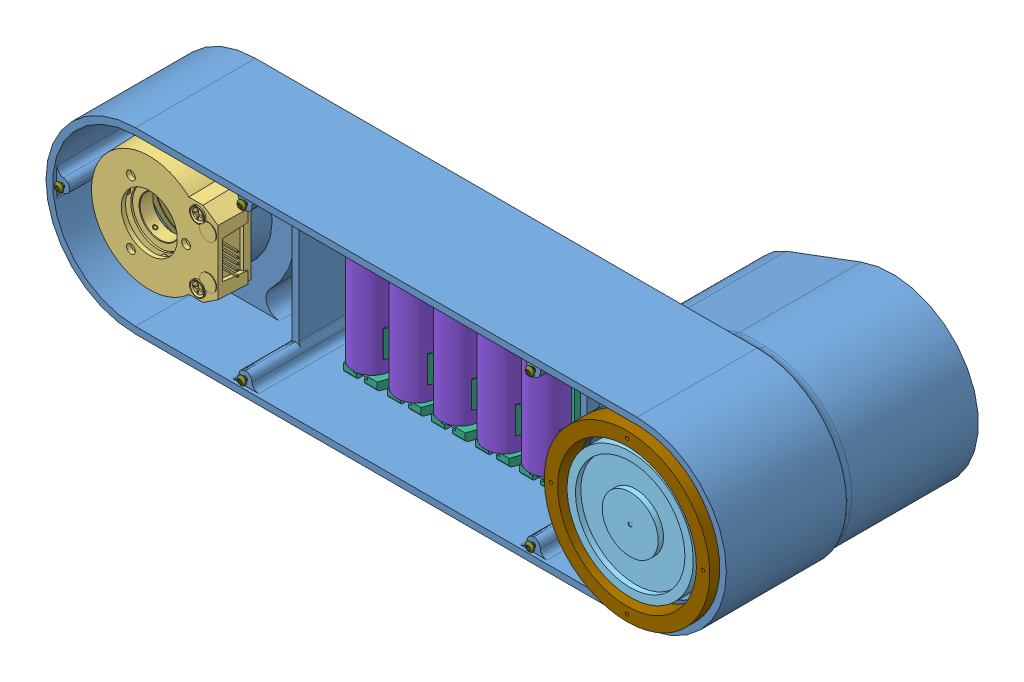
SolidWorks assembly Wall Link, configuration Default. Lengths in mm.
Overall size (323.85 85.09 127.22).
64 component instances, 23 part files, 117 mates.
Components (placement in the parent):
- Wall Link Frame-1: Wall Link Frame [Default] at (-125.008 20.7132 -31.1742) size (323.85 85.09 121.22)
- ring_gear-1: ring_gear [Default] at (-125.008 20.7132 -35.0242) x (0 0 -1) z (1 0 0) size (5 75 75)
- Magnet Encoders E3-X-750-X-H-D-X-1: Magnet Encoders E3-X-750-X-H-D-X [Default] at (113.752 20.7132 -54.2232) x (0 1 0) z (-1 0 0) size (55.98 16.26 66.52)
- magnet holder-1: magnet holder [Default] at (117.5304 22.0262 -2.1382) x (0.944598 0.32823 0) z (-0.32823 0.944598 0) size (50.8 63.9 50.6)
- EM237 Magnet-1: EM237 Magnet [Default] at (113.752 20.7132 10.3713) x (-0.997847 -0.065578 0) z (-0.065578 0.997847 0) size (60.08 25.02 60.08)
- PCB_Battery Assembly-3: PCB_Battery Assembly [Default] at (90.4555 -0.9181 88.7233) x (1 0 0) z (0 1 0) size (117.17 24.87 77.22)
  - Battery Holder - keystone-PN1043-1: Battery Holder - keystone-PN1043 [Default] at (-125.3925 103.3982 18.9155) x (1 0 0) z (0 0 -1) size (20.65 18.93 77.14)
  - Battery PCB-1: Battery PCB [Default] at (-148.3186 115.135 -16.9005) x (1 0 0) z (0 -1 0) size (117.17 77.06 1.59)
  - battery_6612-1: battery_6612 [Default] at (-117.0385 104.4035 -11.3639) x (-0.413992 0.91028 0) z (0.91028 0.413992 0) size (18.3 65.05 18.3)
  - battery_6612-2: battery_6612 [Default] at (-137.9935 104.4035 54.6265) x (-0.916106 0.400937 0) z (-0.400937 -0.916106 0) size (18.3 65.05 18.3)
  - Battery Holder - keystone-PN1043-2: Battery Holder - keystone-PN1043 [Default] at (-129.6396 103.3982 24.3471) x (-1 0 0) z (0 0 1) size (20.65 18.93 77.14)
  - Battery Holder - keystone-PN1043-3: Battery Holder - keystone-PN1043 [Default] at (-104.4375 103.3982 18.9155) x (1 0 0) z (0 0 -1) size (20.65 18.93 77.14)
  - battery_6612-3: battery_6612 [Default] at (-96.0835 104.4035 -10.3735) x (1 0 0) z (0 -1 0) size (18.3 65.05 18.3)
  - Battery Holder - keystone-PN1043-4: Battery Holder - keystone-PN1043 [Default] at (-83.4825 103.3982 18.9155) x (1 0 0) z (0 0 -1) size (20.65 18.93 77.14)
  - Battery Holder - keystone-PN1043-5: Battery Holder - keystone-PN1043 [Default] at (-45.8196 103.3982 24.3471) x (-1 0 0) z (0 0 1) size (20.65 18.93 77.14)
  - battery_6612-4: battery_6612 [Default] at (-75.1285 104.4035 -11.3639) x (-0.923728 -0.383049 0) z (-0.383049 0.923728 0) size (18.3 65.05 18.3)
  - battery_6612-5: battery_6612 [Default] at (-54.1735 104.4035 54.6265) x (-1 0 0) z (0 -1 0) size (18.3 65.05 18.3)
- Delrin_Ring-1: Delrin_Ring [Default] at (113.752 20.7132 24.3883) x (1 0 0) z (0 1 0) size (78.74 9.53 78.74)
- Neoprene Ring-1: Neoprene Ring [Default] at (113.752 20.7132 14.8633) x (0 1 0) z (-1 0 0) size (78.74 3.17 78.74)
- Slip Ring M322M1-0600-1: Slip Ring M322M1-0600 [Default] at (113.752 20.7132 -74.8152) x (0.866025 0.5 0) z (0 0 1) size (44 44 48)
- Wall Link Acrylic Cover-1: Wall Link Acrylic Cover [Default] at (113.752 20.7132 18.0383) x (-1 0 0) z (0 1 0) size (252.86 1.59 78.74) (hidden)
- Magnet Encoders E3-X-750-X-H-D-X-2: Magnet Encoders E3-X-750-X-H-D-X [Default] at (-125.008 20.7132 0.8148) x (0 1 0) z (1 0 0) size (55.98 16.26 66.52)
- Acrylic Cover 2 Wall Link-1: Acrylic Cover 2 Wall Link [Default] at (113.752 20.7132 -101.5942) x (-1 0 0) z (0 0 1) size (102.62 76.2 1.59) (hidden)
- Bearing - .750-1: Bearing - .750 [3760T241] at (-125.008 20.7132 -11.3454) x (-0.923728 -0.383049 0) z (0 0 -1) size (41.27 41.27 11.11)
- Bearing - .750-3: Bearing - .750 [3760T241] at (113.752 20.7132 -27.7755) size (41.27 41.27 11.11)
- Bearing - .750-2: Bearing - .750 [3760T241] at (113.752 20.7132 -38.888) x (0.923728 0.383049 0) z (0 0 -1) size (41.27 41.27 11.11)
- .75 Bore External Retaining Ring-1: .75 Bore External Retaining Ring [97633A250] at (113.752 21.2592 -44.9776) x (0 0 -1) z (1 0 0) size (1.07 23.39 21.18)
- 1.625 Bore Internal Retaining Ring-2: 1.625 Bore Internal Retaining Ring [99142A560] at (113.752 20.7132 -20.6444) x (1 0 0) z (0 -1 0) size (45.82 1.57 43.68)
- Dowel Pin - .0625-1: Dowel Pin - .0625 [97395A414] at (113.752 -15.4818 8.5133) x (0 0 1) z (0.923728 0.383049 0) size (19.05 1.59 1.59)
- Dowel Pin - .0625-2: Dowel Pin - .0625 [97395A414] at (113.752 56.9082 8.5133) x (0 0 1) z (0.923728 0.383049 0) size (19.05 1.59 1.59)
- Dowel Pin - .0625-3: Dowel Pin - .0625 [97395A414] at (149.947 20.7132 8.5133) x (0 0 1) z (0.923728 0.383049 0) size (19.05 1.59 1.59)
- Dowel Pin - .0625-4: Dowel Pin - .0625 [97395A414] at (77.557 20.7132 8.5133) x (0 0 1) z (0.923728 0.383049 0) size (19.05 1.59 1.59)
- 2-56 Screw-1: 2-56 Screw [98164A427] at (62.952 -15.4818 20.7942) size (4.17 4.17 10.95)
- 2-56 Screw-2: 2-56 Screw [98164A427] at (62.952 56.9082 20.7942) size (4.17 4.17 10.95)
- 2-56 Screw-3: 2-56 Screw [98164A427] at (-74.208 56.9082 20.7942) size (4.17 4.17 10.95)
- 2-56 Screw-4: 2-56 Screw [98164A427] at (-161.203 20.7132 20.7942) size (4.17 4.17 10.95)
- 2-56 Screw-5: 2-56 Screw [98164A427] at (-74.208 -15.4818 20.7942) size (4.17 4.17 10.95)
- M5 Screws-1: M5 Screws [91352A131] at (122.502 35.8687 -77.5652) x (-0.923728 -0.383049 0) z (0 0 -1) size (9.5 9.5 13.21)
- M5 Screws-2: M5 Screws [91352A131] at (122.502 5.5578 -77.5652) x (0.923728 0.383049 0) z (0 0 -1) size (9.5 9.5 13.21)
- M5 Screws-3: M5 Screws [91352A131] at (96.252 20.7132 -77.5652) x (-0.923728 -0.383049 0) z (0 0 -1) size (9.5 9.5 13.21)
- M5 Nylon Spacer-1: M5 Nylon Spacer [93657A042] at (122.502 35.8687 -69.4152) size (8 8 6)
- M5 Nylon Spacer-2: M5 Nylon Spacer [93657A042] at (96.252 20.7132 -69.4152) size (8 8 6)
- M5 Nylon Spacer-3: M5 Nylon Spacer [93657A042] at (122.502 5.5578 -69.4152) size (8 8 6)
- 4-40 Screws-1: 4-40 Screws [92949A108] at (-125.008 43.7256 2.3134) size (5.41 5.41 11.35)
- 4-40 Screws-2: 4-40 Screws [92949A108] at (113.752 -2.2992 -55.7218) x (0.923728 0.383049 0) z (0 0 -1) size (5.41 5.41 11.35)
- 4-40 Screws-3: 4-40 Screws [92949A108] at (113.752 43.7256 -55.7218) x (0.923728 0.383049 0) z (0 0 -1) size (5.41 5.41 11.35)
- 4-40 Screws-4: 4-40 Screws [92949A108] at (-125.008 -2.2992 2.3134) x (0.999053 -0.043504 0) z (0 0 1) size (5.41 5.41 11.35)
- 2-56 Screw-6: 2-56 Screw [98164A427] at (52.4103 20.7132 -102.7626) x (-0.923728 -0.383049 0) z (0 0 -1) size (4.17 4.17 10.95)
- 2-56 Screw-7: 2-56 Screw [98164A427] at (148.677 20.7132 -102.7626) x (-0.923728 -0.383049 0) z (0 0 -1) size (4.17 4.17 10.95)
- 2-56 Screw-8: 2-56 Screw [98164A427] at (88.352 48.4953 -102.7626) x (-0.923728 -0.383049 0) z (0 0 -1) size (4.17 4.17 10.95)
- 2-56 Screw-9: 2-56 Screw [98164A427] at (88.352 -7.0688 -102.7626) x (-0.923728 -0.383049 0) z (0 0 -1) size (4.17 4.17 10.95)
- 2-56 Screw-10: 2-56 Screw [98164A427] at (49.7821 52.895 -23.6558) size (4.17 4.17 10.95)
- 2-56 Screw-12: 2-56 Screw [98164A427] at (49.7821 -11.4686 -23.6558) size (4.17 4.17 10.95)
- 2-56 Screw-13: 2-56 Screw [98164A427] at (-61.0381 52.895 -23.6558) size (4.17 4.17 10.95)
- 2-56 Screw-14: 2-56 Screw [98164A427] at (-61.0381 -11.4686 -23.6558) size (4.17 4.17 10.95)
- #2 Spacer-1: #2 Spacer [94639A188] at (49.7821 52.895 -28.793) x (0.8148 0.579742 0) z (0 0 1) size (6.35 6.35 4.76)
- #2 Spacer-2: #2 Spacer [94639A188] at (49.7821 -11.4686 -28.793) x (0.211674 0.97734 0) z (0 0 1) size (6.35 6.35 4.76)
- #2 Spacer-3: #2 Spacer [94639A188] at (-61.0381 52.895 -28.793) x (0.886571 -0.462592 0) z (0 0 1) size (6.35 6.35 4.76)
- #2 Spacer-4: #2 Spacer [94639A188] at (-61.0381 -11.4686 -28.793) x (-0.923728 -0.383049 0) z (0 0 -1) size (6.35 6.35 4.76)
- 8-32 Low Profile Screws-1: 8-32 Low Profile Screws [92220A153] at (-125.008 -13.5768 -31.1742) x (0 0 1) z (-1 0 0) size (15.09 6.86 6.86)
- 8-32 Low Profile Screws-2: 8-32 Low Profile Screws [92220A153] at (-90.718 20.7132 -31.1742) x (0 0 1) z (-1 0 0) size (15.09 6.86 6.86)
- 8-32 Low Profile Screws-3: 8-32 Low Profile Screws [92220A153] at (-125.008 55.0032 -31.1742) x (0 0 1) z (-0.52487 0.851182 0) size (15.09 6.86 6.86)
- 8-32 Low Profile Screws-4: 8-32 Low Profile Screws [92220A153] at (-159.298 20.7132 -31.1742) x (0 0 1) z (-1 0 0) size (15.09 6.86 6.86)
- 1.625 Bore Internal Retaining Ring-3: 1.625 Bore Internal Retaining Ring [99142A560] at (-125.008 20.7132 -5.7892) x (1 0 0) z (0 1 0) size (45.82 1.57 43.68)
Mates (geometry in assembly coordinates):
- Coincident1: coincident aligned: plane of Wall Link Frame-1 through (-125.008 20.7132 -37.5242) normal (0 0 -1); plane of ring_gear-1 through (-125.008 20.7132 -37.5242) normal (0 0 -1)
- Coincident2: coincident aligned: line of Wall Link Frame-1 through (-125.008 20.7132 -32.4442) axis (0 0 -1); line of ring_gear-1 through (-125.008 20.7132 -32.5242) axis (0 0 -1)
- Concentric1: concentric anti-aligned: cylinder of Magnet Encoders E3-X-750-X-H-D-X-1 through (113.752 20.7132 -60.7764) axis (0 0 -1) radius 9.5263; line of Wall Link Frame-1 through (113.752 20.7132 -50.7942) axis (0 0 1)
- Coincident4: coincident anti-aligned: plane of Wall Link Frame-1 through (-125.008 20.7132 -50.7942) normal (0 0 -1); plane of Magnet Encoders E3-X-750-X-H-D-X-1 through (113.752 20.7132 -50.7942) normal (0 0 1)
- Perpendicular1: perpendicular: line of Wall Link Frame-1 through (113.752 20.7132 -31.1742) axis (-1 0 0); line of Magnet Encoders E3-X-750-X-H-D-X-1 through (81.0095 36.0106 -66.4152) axis (0 -1 0)
- Coincident7: coincident aligned: line of Wall Link Frame-1 through (113.752 20.7132 -50.7942) axis (0 0 1); line of magnet holder-1 through (113.752 20.7132 -66.0342) axis (0 0 1)
- Coincident8: coincident aligned: plane of magnet holder-1; plane of EM237 Magnet-1 through (113.752 20.7132 -2.1382) normal (0 0 -1)
- Concentric2: concentric anti-aligned: line of Wall Link Frame-1 through (113.752 20.7132 -50.7942) axis (0 0 1); cylinder of EM237 Magnet-1 through (113.752 20.7132 22.8808) axis (0 0 -1) radius 30.0419
- Coincident12: coincident anti-aligned: plane of Wall Link Frame-1 through (-125.008 20.7132 -16.9017) normal (0 0 1); plane of Bearing - .750-1 through (-132.7004 39.2634 -16.9017) normal (0 0 -1)
- Coincident13: coincident anti-aligned: line of Wall Link Frame-1 through (-125.008 20.7132 -32.4442) axis (0 0 -1); line of Bearing - .750-1 through (-125.008 20.7132 -16.9017) axis (0 0 1)
- Concentric4: concentric anti-aligned: line of Wall Link Frame-1 through (-125.008 20.7132 -32.4442) axis (0 0 -1); cylinder of Magnet Encoders E3-X-750-X-H-D-X-2 through (-125.008 20.7132 64.3727) axis (0 0 1) radius 9.5263
- Parallel1: parallel: line of Wall Link Frame-1 through (113.752 20.7132 -31.1742) axis (-1 0 0); plane of Magnet Encoders E3-X-750-X-H-D-X-2 through (-99.2764 41.2364 56.2447) normal (0 0.999391 0.034899)
- Concentric5: concentric aligned: line of Wall Link Frame-1 through (113.752 20.7132 19.6258) axis (0 0 -1); cylinder of Bearing - .750-2 through (113.752 20.7132 -44.4442) axis (0 0 -1) radius 20.6375
- Coincident20: coincident anti-aligned: plane of Wall Link Frame-1 through (113.752 20.7132 -44.4442) normal (0 0 1); plane of Bearing - .750-2 through (121.4443 2.1631 -44.4442) normal (0 0 -1)
- Concentric6: concentric anti-aligned: cylinder of Bearing - .750-3 through (113.752 20.7132 -22.2192) axis (0 0 1) radius 20.6375; line of Wall Link Frame-1 through (113.752 20.7132 19.6258) axis (0 0 -1)
- Coincident21: coincident anti-aligned: plane of Bearing - .750-2 through (121.4443 2.1631 -33.3317) normal (0 0 1); plane of Bearing - .750-3 through (113.752 40.7951 -33.3317) normal (0 0 -1)
- Coincident22: coincident anti-aligned: plane of Wall Link Frame-1 through (113.752 20.7132 -22.2192) normal (0 0 1); plane of 1.625 Bore Internal Retaining Ring-2 through (124.7408 3.9692 -22.2192) normal (0 0 -1)
- Concentric7: concentric anti-aligned: line of Wall Link Frame-1 through (113.752 20.7132 19.6258) axis (0 0 -1); cylinder of 1.625 Bore Internal Retaining Ring-2 through (113.752 20.7132 -22.2192) axis (0 0 1) radius 22.9108
- Coincident24: coincident anti-aligned: plane of magnet holder-1 through (125.7484 24.8818 -22.2192) normal (0 0 -1); plane of Bearing - .750-3 through (113.752 34.4687 -22.2192) normal (0 0 1)
- Coincident25: coincident anti-aligned: plane of magnet holder-1 through (113.752 20.7132 -44.4442) normal (0 0 -1); plane of .75 Bore External Retaining Ring-1 through (113.752 21.2592 -44.4442) normal (0 0 1)
- Concentric8: concentric anti-aligned: line of Wall Link Frame-1 through (113.752 20.7132 19.6258) axis (0 0 -1); cylinder of .75 Bore External Retaining Ring-1 through (113.752 20.7132 -45.511) axis (0 0 1) radius 10.592
- Concentric10: concentric anti-aligned: line of Wall Link Frame-1 through (113.752 20.7132 19.6258) axis (0 0 -1); cylinder of Neoprene Ring-1 through (113.752 20.7132 11.6883) axis (0 0 1) radius 33.02
- Concentric9: concentric aligned: cylinder of Wall Link Frame-1 through (77.557 20.7132 -1.0117) axis (0 0 1) radius 0.7937; cylinder of Neoprene Ring-1 through (77.557 20.7132 11.6883) axis (0 0 1) radius 0.7937
- Coincident27: coincident anti-aligned: plane of Wall Link Frame-1 through (113.752 20.7132 11.6883) normal (0 0 1); plane of Neoprene Ring-1 through (113.752 20.7132 11.6883) normal (0 0 -1)
- Coincident28: coincident anti-aligned: plane of Delrin_Ring-1 through (113.752 20.7132 14.8633) normal (0 0 -1); plane of Neoprene Ring-1 through (113.752 20.7132 14.8633) normal (0 0 1)
- Concentric11: concentric anti-aligned: line of Wall Link Frame-1 through (113.752 20.7132 19.6258) axis (0 0 -1); cylinder of Delrin_Ring-1 through (113.752 20.7132 14.8633) axis (0 0 1) radius 33.02
- Concentric12: concentric aligned: cylinder of Wall Link Frame-1 through (77.557 20.7132 -1.0117) axis (0 0 1) radius 0.7937; cylinder of Delrin_Ring-1 through (77.557 20.7132 14.8633) axis (0 0 1) radius 0.7937
- Concentric13: concentric aligned: cylinder of Wall Link Frame-1 through (77.557 20.7132 -1.0117) axis (0 0 1) radius 0.7937; cylinder of Dowel Pin - .0625-4 through (77.557 20.7132 -1.0117) axis (0 0 1) radius 0.7937
- Coincident30: coincident anti-aligned: plane of Wall Link Frame-1 through (77.557 20.7132 -1.0117) normal (0 0 1); plane of Dowel Pin - .0625-4 through (77.557 20.7132 -1.0117) normal (0 0 -1)
- Concentric15: concentric aligned: cylinder of Wall Link Frame-1 through (113.752 -15.4818 -1.0117) axis (0 0 1) radius 0.7937; cylinder of Dowel Pin - .0625-1 through (113.752 -15.4818 -1.0117) axis (0 0 1) radius 0.7937
- Coincident31: coincident anti-aligned: plane of Wall Link Frame-1 through (113.752 -15.4818 -1.0117) normal (0 0 1); plane of Dowel Pin - .0625-1 through (113.752 -15.4818 -1.0117) normal (0 0 -1)
- Concentric16: concentric aligned: cylinder of Wall Link Frame-1 through (149.947 20.7132 -1.0117) axis (0 0 1) radius 0.7937; cylinder of Dowel Pin - .0625-3 through (149.947 20.7132 -1.0117) axis (0 0 1) radius 0.7937
- Coincident32: coincident anti-aligned: plane of Wall Link Frame-1 through (149.947 20.7132 -1.0117) normal (0 0 1); plane of Dowel Pin - .0625-3 through (149.947 20.7132 -1.0117) normal (0 0 -1)
- Concentric17: concentric aligned: cylinder of Wall Link Frame-1 through (113.752 56.9082 -1.0117) axis (0 0 1) radius 0.7937; cylinder of Dowel Pin - .0625-2 through (113.752 56.9082 -1.0117) axis (0 0 1) radius 0.7937
- Coincident33: coincident anti-aligned: plane of Wall Link Frame-1 through (113.752 56.9082 -1.0117) normal (0 0 1); plane of Dowel Pin - .0625-2 through (113.752 56.9082 -1.0117) normal (0 0 -1)
- Concentric19: concentric aligned: line of Wall Link Frame-1 through (113.752 20.7132 19.6258) axis (0 0 -1); cylinder of Slip Ring M322M1-0600-1 through (113.752 20.7132 -58.4152) axis (0 0 -1) radius 3.8
- Distance1: distance = 6 mm anti-aligned: plane of Slip Ring M322M1-0600-1 through (132.8045 31.7132 -72.4152) normal (0 0 1); plane of Magnet Encoders E3-X-750-X-H-D-X-1 through (113.752 20.7132 -66.4152) normal (0 0 -1)
- Coincident34: coincident anti-aligned: plane of Wall Link Frame-1 through (-125.008 20.7132 18.0383) normal (0 0 1); plane of Wall Link Acrylic Cover-1 through (-125.008 20.7132 18.0383) normal (0 0 -1)
- Concentric20: concentric anti-aligned: cylinder of Wall Link Frame-1 through (-161.203 20.7132 18.0383) axis (0 0 1) radius 0.889; cylinder of Wall Link Acrylic Cover-1 through (-161.203 20.7132 19.6258) axis (0 0 -1) radius 1.0922
- Concentric21: concentric anti-aligned: cylinder of Wall Link Frame-1 through (-74.208 56.9082 18.0383) axis (0 0 1) radius 0.889; cylinder of Wall Link Acrylic Cover-1 through (-74.208 56.9082 19.6258) axis (0 0 -1) radius 1.0922
- Concentric22: concentric anti-aligned: cylinder of Wall Link Acrylic Cover-1 through (62.952 -15.4818 19.6258) axis (0 0 -1) radius 1.0922; line of 2-56 Screw-1 through (62.952 -15.4818 10.1008) axis (0 0 1)
- Coincident36: coincident anti-aligned: plane of Wall Link Acrylic Cover-1 through (-125.008 20.7132 19.6258) normal (0 0 1); plane of 2-56 Screw-1 through (62.952 -17.5646 19.6258) normal (0 0 -1)
- Concentric23: concentric anti-aligned: line of 2-56 Screw-2 through (62.952 56.9082 10.1008) axis (0 0 1); cylinder of Wall Link Acrylic Cover-1 through (62.952 56.9082 19.6258) axis (0 0 -1) radius 1.0922
- Coincident37: coincident anti-aligned: plane of Wall Link Acrylic Cover-1 through (-125.008 20.7132 19.6258) normal (0 0 1); plane of 2-56 Screw-2 through (62.952 54.8254 19.6258) normal (0 0 -1)
- Concentric24: concentric anti-aligned: cylinder of Wall Link Acrylic Cover-1 through (-74.208 56.9082 19.6258) axis (0 0 -1) radius 1.0922; line of 2-56 Screw-3 through (-74.208 56.9082 10.1008) axis (0 0 1)
- Coincident39: coincident anti-aligned: plane of Wall Link Acrylic Cover-1 through (-125.008 20.7132 19.6258) normal (0 0 1); plane of 2-56 Screw-3 through (-74.208 54.8254 19.6258) normal (0 0 -1)
- Concentric25: concentric anti-aligned: cylinder of Wall Link Acrylic Cover-1 through (-74.208 -15.4818 19.6258) axis (0 0 -1) radius 1.0922; line of 2-56 Screw-5 through (-74.208 -15.4818 10.1008) axis (0 0 1)
- Coincident41: coincident anti-aligned: plane of Wall Link Acrylic Cover-1 through (-125.008 20.7132 19.6258) normal (0 0 1); plane of 2-56 Screw-5 through (-74.208 -17.5646 19.6258) normal (0 0 -1)
- Concentric26: concentric anti-aligned: cylinder of Wall Link Acrylic Cover-1 through (-161.203 20.7132 19.6258) axis (0 0 -1) radius 1.0922; line of 2-56 Screw-4 through (-161.203 20.7132 10.1008) axis (0 0 1)
- Coincident43: coincident anti-aligned: plane of Wall Link Acrylic Cover-1 through (-125.008 20.7132 19.6258) normal (0 0 1); plane of 2-56 Screw-4 through (-161.203 18.6304 19.6258) normal (0 0 -1)
- Concentric27: concentric aligned: cylinder of Magnet Encoders E3-X-750-X-H-D-X-1 through (96.252 20.7132 -66.4152) axis (0 0 -1) radius 2.1; cylinder of Slip Ring M322M1-0600-1 through (96.252 20.7132 -74.8152) axis (0 0 -1) radius 2.75
- Concentric29: concentric aligned: cylinder of Magnet Encoders E3-X-750-X-H-D-X-1 through (122.502 5.5578 -66.4152) axis (0 0 -1) radius 2.1; cylinder of Slip Ring M322M1-0600-1 through (122.502 5.5578 -74.8152) axis (0 0 -1) radius 2.75
- Concentric30: concentric aligned: cylinder of Magnet Encoders E3-X-750-X-H-D-X-1 through (122.502 35.8687 -66.4152) axis (0 0 -1) radius 2.1; cylinder of Slip Ring M322M1-0600-1 through (122.502 35.8687 -74.8152) axis (0 0 -1) radius 2.75
- Concentric31: concentric aligned: cylinder of Slip Ring M322M1-0600-1 through (96.252 20.7132 -74.8152) axis (0 0 -1) radius 2.75; line of M5 Screws-3 through (96.252 20.7132 -64.8152) axis (0 0 -1)
- Coincident45: coincident anti-aligned: plane of Slip Ring M322M1-0600-1 through (113.752 20.7132 -74.8152) normal (0 0 -1); plane of M5 Screws-3 through (98.0714 16.3255 -74.8152) normal (0 0 1)
- Concentric32: concentric aligned: cylinder of Slip Ring M322M1-0600-1 through (122.502 35.8687 -74.8152) axis (0 0 -1) radius 2.75; line of M5 Screws-1 through (122.502 35.8687 -64.8152) axis (0 0 -1)
- Coincident47: coincident anti-aligned: plane of Slip Ring M322M1-0600-1 through (113.752 20.7132 -74.8152) normal (0 0 -1); plane of M5 Screws-1 through (124.3214 31.481 -74.8152) normal (0 0 1)
- Concentric33: concentric aligned: cylinder of Slip Ring M322M1-0600-1 through (122.502 5.5578 -74.8152) axis (0 0 -1) radius 2.75; line of M5 Screws-2 through (122.502 5.5578 -64.8152) axis (0 0 -1)
- Coincident49: coincident anti-aligned: plane of Slip Ring M322M1-0600-1 through (113.752 20.7132 -74.8152) normal (0 0 -1); plane of M5 Screws-2 through (120.6825 9.9455 -74.8152) normal (0 0 1)
- Concentric34: concentric aligned: cylinder of Slip Ring M322M1-0600-1 through (96.252 20.7132 -74.8152) axis (0 0 -1) radius 2.75; cylinder of M5 Nylon Spacer-2 through (96.252 20.7132 -66.4152) axis (0 0 -1) radius 2.65
- Coincident50: coincident anti-aligned: plane of Magnet Encoders E3-X-750-X-H-D-X-1 through (113.752 20.7132 -66.4152) normal (0 0 -1); plane of M5 Nylon Spacer-2 through (96.252 20.7132 -66.4152) normal (0 0 1)
- Coincident51: coincident anti-aligned: plane of Magnet Encoders E3-X-750-X-H-D-X-1 through (113.752 20.7132 -66.4152) normal (0 0 -1); plane of M5 Nylon Spacer-1 through (122.502 35.8687 -66.4152) normal (0 0 1)
- Concentric35: concentric aligned: cylinder of Slip Ring M322M1-0600-1 through (122.502 35.8687 -74.8152) axis (0 0 -1) radius 2.75; cylinder of M5 Nylon Spacer-1 through (122.502 35.8687 -66.4152) axis (0 0 -1) radius 2.65
- Concentric36: concentric aligned: cylinder of Slip Ring M322M1-0600-1 through (122.502 5.5578 -74.8152) axis (0 0 -1) radius 2.75; cylinder of M5 Nylon Spacer-3 through (122.502 5.5578 -66.4152) axis (0 0 -1) radius 2.65
- Coincident52: coincident anti-aligned: plane of Magnet Encoders E3-X-750-X-H-D-X-1 through (113.752 20.7132 -66.4152) normal (0 0 -1); plane of M5 Nylon Spacer-3 through (122.502 5.5578 -66.4152) normal (0 0 1)
- Concentric37: concentric aligned: cylinder of Wall Link Frame-1 through (-90.718 20.7132 -32.4442) axis (0 0 -1) radius 1.7272; cylinder of ring_gear-1 through (-90.718 20.7132 -32.5242) axis (0 0 -1) radius 2.1526
- Concentric42: concentric anti-aligned: cylinder of Magnet Encoders E3-X-750-X-H-D-X-2 through (-125.008 43.7256 57.8195) axis (0 0 -1) radius 1.4351; line of 4-40 Screws-1 through (-125.008 43.7256 48.2945) axis (0 0 1)
- Coincident62: coincident anti-aligned: plane of Magnet Encoders E3-X-750-X-H-D-X-2 through (-125.008 20.7132 57.8195) normal (0 0 1); plane of 4-40 Screws-1 through (-125.008 41.0205 57.8195) normal (0 0 -1)
- Concentric43: concentric anti-aligned: cylinder of Magnet Encoders E3-X-750-X-H-D-X-2 through (-125.008 -2.2992 57.8195) axis (0 0 -1) radius 1.4351; line of 4-40 Screws-4 through (-125.008 -2.2992 48.2945) axis (0 0 1)
- Coincident64: coincident anti-aligned: plane of Magnet Encoders E3-X-750-X-H-D-X-2 through (-125.008 20.7132 57.8195) normal (0 0 1); plane of 4-40 Screws-4 through (-125.1257 -5.0017 57.8195) normal (0 0 -1)
- Concentric44: concentric anti-aligned: cylinder of Magnet Encoders E3-X-750-X-H-D-X-1 through (113.752 43.7256 -54.2232) axis (0 0 1) radius 1.4351; line of 4-40 Screws-3 through (113.752 43.7256 -44.6982) axis (0 0 -1)
- Coincident66: coincident anti-aligned: plane of Magnet Encoders E3-X-750-X-H-D-X-1 through (113.752 20.7132 -54.2232) normal (0 0 -1); plane of 4-40 Screws-3 through (112.7158 46.2244 -54.2232) normal (0 0 1)
- Concentric45: concentric anti-aligned: cylinder of Magnet Encoders E3-X-750-X-H-D-X-1 through (113.752 -2.2992 -54.2232) axis (0 0 1) radius 1.4351; line of 4-40 Screws-2 through (113.752 -2.2992 -44.6982) axis (0 0 -1)
- Coincident68: coincident anti-aligned: plane of Magnet Encoders E3-X-750-X-H-D-X-1 through (113.752 20.7132 -54.2232) normal (0 0 -1); plane of 4-40 Screws-2 through (112.7158 0.1996 -54.2232) normal (0 0 1)
- Coincident69: coincident anti-aligned: plane of Wall Link Frame-1 through (-125.008 20.7132 -100.0067) normal (0 0 -1); plane of Acrylic Cover 2 Wall Link-1 through (113.752 20.7132 -100.0067) normal (0 0 1)
- Concentric46: concentric aligned: cylinder of Wall Link Frame-1 through (148.677 20.7132 -100.0067) axis (0 0 -1) radius 0.889; cylinder of Acrylic Cover 2 Wall Link-1 through (148.677 20.7132 -100.0067) axis (0 0 -1) radius 1.0922
- Concentric47: concentric aligned: cylinder of Wall Link Frame-1 through (52.4103 20.7132 -100.0067) axis (0 0 -1) radius 0.889; cylinder of Acrylic Cover 2 Wall Link-1 through (52.4103 20.7132 -100.0067) axis (0 0 -1) radius 1.0922
- Concentric48: concentric aligned: cylinder of Wall Link Frame-1 through (88.352 48.4953 -100.0067) axis (0 0 -1) radius 0.889; cylinder of Acrylic Cover 2 Wall Link-1 through (88.352 48.4953 -100.0067) axis (0 0 -1) radius 1.0922
- Concentric49: concentric aligned: cylinder of Wall Link Frame-1 through (88.352 -7.0688 -100.0067) axis (0 0 -1) radius 0.889; cylinder of Acrylic Cover 2 Wall Link-1 through (88.352 -7.0688 -100.0067) axis (0 0 -1) radius 1.0922
- Coincident70: coincident anti-aligned: plane of Acrylic Cover 2 Wall Link-1 through (113.752 20.7132 -101.5942) normal (0 0 -1); plane of 2-56 Screw-7 through (149.4748 18.7893 -101.5942) normal (0 0 1)
- Concentric51: concentric aligned: cylinder of Acrylic Cover 2 Wall Link-1 through (148.677 20.7132 -100.0067) axis (0 0 -1) radius 1.0922; cylinder of 2-56 Screw-7 through (148.677 20.7132 -102.7626) axis (0 0 -1) radius 2.0828
- Coincident71: coincident anti-aligned: plane of Acrylic Cover 2 Wall Link-1 through (113.752 20.7132 -101.5942) normal (0 0 -1); plane of 2-56 Screw-9 through (89.1498 -8.9927 -101.5942) normal (0 0 1)
- Concentric52: concentric aligned: cylinder of Acrylic Cover 2 Wall Link-1 through (88.352 -7.0688 -100.0067) axis (0 0 -1) radius 1.0922; cylinder of 2-56 Screw-9 through (88.352 -7.0688 -102.7626) axis (0 0 -1) radius 2.0828
- Coincident72: coincident anti-aligned: plane of Acrylic Cover 2 Wall Link-1 through (113.752 20.7132 -101.5942) normal (0 0 -1); plane of 2-56 Screw-8 through (89.1498 46.5713 -101.5942) normal (0 0 1)
- Concentric53: concentric aligned: cylinder of Acrylic Cover 2 Wall Link-1 through (88.352 48.4953 -100.0067) axis (0 0 -1) radius 1.0922; cylinder of 2-56 Screw-8 through (88.352 48.4953 -102.7626) axis (0 0 -1) radius 2.0828
- Coincident73: coincident anti-aligned: plane of Acrylic Cover 2 Wall Link-1 through (113.752 20.7132 -101.5942) normal (0 0 -1); plane of 2-56 Screw-6 through (53.2081 18.7893 -101.5942) normal (0 0 1)
- Concentric54: concentric aligned: cylinder of Acrylic Cover 2 Wall Link-1 through (52.4103 20.7132 -100.0067) axis (0 0 -1) radius 1.0922; cylinder of 2-56 Screw-6 through (52.4103 20.7132 -102.7626) axis (0 0 -1) radius 2.0828
- Concentric55: concentric anti-aligned: cylinder of PCB_Battery Assembly-3/Battery PCB-1 through (49.7821 52.895 -24.8242) axis (0 0 -1) radius 1.0922; cylinder of 2-56 Screw-10 through (49.7821 52.895 -23.6558) axis (0 0 1) radius 2.0828
- Coincident74: coincident anti-aligned: plane of PCB_Battery Assembly-3/Battery PCB-1 through (-57.8631 -17.8186 -24.8242) normal (0 0 1); plane of 2-56 Screw-10 through (49.7821 50.8122 -24.8242) normal (0 0 -1)
- Concentric56: concentric anti-aligned: cylinder of PCB_Battery Assembly-3/Battery PCB-1 through (49.7821 -11.4686 -24.8242) axis (0 0 -1) radius 1.0922; cylinder of 2-56 Screw-12 through (49.7821 -11.4686 -23.6558) axis (0 0 1) radius 2.0828
- Coincident75: coincident anti-aligned: plane of PCB_Battery Assembly-3/Battery PCB-1 through (-57.8631 -17.8186 -24.8242) normal (0 0 1); plane of 2-56 Screw-12 through (49.7821 -13.5514 -24.8242) normal (0 0 -1)
- Concentric57: concentric anti-aligned: cylinder of PCB_Battery Assembly-3/Battery PCB-1 through (-61.0381 52.895 -24.8242) axis (0 0 -1) radius 1.0922; cylinder of 2-56 Screw-13 through (-61.0381 52.895 -23.6558) axis (0 0 1) radius 2.0828
- Coincident76: coincident anti-aligned: plane of PCB_Battery Assembly-3/Battery PCB-1 through (-57.8631 -17.8186 -24.8242) normal (0 0 1); plane of 2-56 Screw-13 through (-61.0381 50.8122 -24.8242) normal (0 0 -1)
- Concentric58: concentric anti-aligned: cylinder of PCB_Battery Assembly-3/Battery PCB-1 through (-61.0381 -11.4686 -24.8242) axis (0 0 -1) radius 1.0922; cylinder of 2-56 Screw-14 through (-61.0381 -11.4686 -23.6558) axis (0 0 1) radius 2.0828
- Coincident77: coincident anti-aligned: plane of PCB_Battery Assembly-3/Battery PCB-1 through (-57.8631 -17.8186 -24.8242) normal (0 0 1); plane of 2-56 Screw-14 through (-61.0381 -13.5514 -24.8242) normal (0 0 -1)
- Concentric59: concentric anti-aligned: cylinder of Wall Link Frame-1 through (49.7821 52.895 -31.1742) axis (0 0 1) radius 0.889; cylinder of #2 Spacer-1 through (49.7821 52.895 -26.4117) axis (0 0 -1) radius 3.175
- Coincident78: coincident anti-aligned: plane of Wall Link Frame-1 through (-125.008 20.7132 -31.1742) normal (0 0 1); plane of #2 Spacer-1 through (49.7821 52.895 -31.1742) normal (0 0 -1)
- Concentric60: concentric anti-aligned: cylinder of Wall Link Frame-1 through (49.7821 -11.4686 -31.1742) axis (0 0 1) radius 0.889; cylinder of #2 Spacer-2 through (49.7821 -11.4686 -26.4117) axis (0 0 -1) radius 1.143
- Coincident79: coincident anti-aligned: plane of Wall Link Frame-1 through (-125.008 20.7132 -31.1742) normal (0 0 1); plane of #2 Spacer-2 through (49.7821 -11.4686 -31.1742) normal (0 0 -1)
- Concentric61: concentric anti-aligned: cylinder of Wall Link Frame-1 through (-61.0381 52.895 -31.1742) axis (0 0 1) radius 0.889; cylinder of #2 Spacer-3 through (-61.0381 52.895 -26.4117) axis (0 0 -1) radius 1.143
- Coincident80: coincident anti-aligned: plane of Wall Link Frame-1 through (-125.008 20.7132 -31.1742) normal (0 0 1); plane of #2 Spacer-3 through (-61.0381 52.895 -31.1742) normal (0 0 -1)
- Coincident81: coincident anti-aligned: plane of Wall Link Frame-1 through (-125.008 20.7132 -31.1742) normal (0 0 1); plane of #2 Spacer-4 through (-61.0381 -11.4686 -31.1742) normal (0 0 -1)
- Concentric62: concentric aligned: cylinder of #2 Spacer-4 through (-61.0381 -11.4686 -31.1742) axis (0 0 1) radius 1.143; cylinder of Wall Link Frame-1 through (-61.0381 -11.4686 -31.1742) axis (0 0 1) radius 0.889
- Coincident82: coincident anti-aligned: plane of PCB_Battery Assembly-3/Battery PCB-1 through (-57.8631 -17.8186 -26.4117) normal (0 0 -1); plane of #2 Spacer-3 through (-61.0381 52.895 -26.4117) normal (0 0 1)
- Concentric63: concentric aligned: cylinder of PCB_Battery Assembly-3/Battery PCB-1 through (-61.0381 52.895 -24.8242) axis (0 0 -1) radius 1.0922; cylinder of #2 Spacer-3 through (-61.0381 52.895 -26.4117) axis (0 0 -1) radius 1.143
- Concentric64: concentric anti-aligned: cylinder of PCB_Battery Assembly-3/Battery PCB-1 through (-61.0381 -11.4686 -24.8242) axis (0 0 -1) radius 1.0922; cylinder of #2 Spacer-4 through (-61.0381 -11.4686 -31.1742) axis (0 0 1) radius 1.143
- Concentric65: concentric anti-aligned: cylinder of ring_gear-1 through (-125.008 -13.5768 -32.5242) axis (0 0 -1) radius 2.1526; cylinder of 8-32 Low Profile Screws-1 through (-125.008 -13.5768 -37.5242) axis (0 0 1) radius 3.429
- Coincident83: coincident anti-aligned: plane of ring_gear-1 through (-125.008 20.7132 -37.5242) normal (0 0 -1); plane of 8-32 Low Profile Screws-1 through (-125.008 -10.1478 -37.5242) normal (0 0 1)
- Concentric66: concentric anti-aligned: cylinder of ring_gear-1 through (-159.298 20.7132 -32.5242) axis (0 0 -1) radius 2.1526; cylinder of 8-32 Low Profile Screws-4 through (-159.298 20.7132 -37.5242) axis (0 0 1) radius 3.429
- Coincident84: coincident anti-aligned: plane of ring_gear-1 through (-125.008 20.7132 -37.5242) normal (0 0 -1); plane of 8-32 Low Profile Screws-4 through (-159.298 24.1422 -37.5242) normal (0 0 1)
- Concentric67: concentric anti-aligned: cylinder of ring_gear-1 through (-125.008 55.0032 -32.5242) axis (0 0 -1) radius 2.1526; cylinder of 8-32 Low Profile Screws-3 through (-125.008 55.0032 -37.5242) axis (0 0 1) radius 3.429
- Coincident85: coincident anti-aligned: plane of ring_gear-1 through (-125.008 20.7132 -37.5242) normal (0 0 -1); plane of 8-32 Low Profile Screws-3 through (-122.0893 56.803 -37.5242) normal (0 0 1)
- Concentric68: concentric anti-aligned: cylinder of ring_gear-1 through (-90.718 20.7132 -32.5242) axis (0 0 -1) radius 2.1526; cylinder of 8-32 Low Profile Screws-2 through (-90.718 20.7132 -37.5242) axis (0 0 1) radius 3.429
- Coincident86: coincident anti-aligned: plane of ring_gear-1 through (-125.008 20.7132 -37.5242) normal (0 0 -1); plane of 8-32 Low Profile Screws-2 through (-90.718 24.1422 -37.5242) normal (0 0 1)
- Coincident87: coincident: plane of Wall Link Frame-1 through (-125.008 20.7132 -5.7892) normal (0 0 1); plane of 1.625 Bore Internal Retaining Ring-3 through (-114.0192 37.4573 -5.7892) normal (0 0 -1)
- Concentric69: concentric aligned: cylinder of Wall Link Frame-1 through (-125.008 20.7132 -4.062) axis (0 0 -1) radius 21.59; cylinder of 1.625 Bore Internal Retaining Ring-3 through (-125.008 20.7132 -4.2144) axis (0 0 -1) radius 22.9108
- Coincident88: coincident anti-aligned: plane of Wall Link Frame-1 through (-125.008 20.7132 -2.6142) normal (0 0 1); plane of Magnet Encoders E3-X-750-X-H-D-X-2 through (-125.008 20.7132 -2.6142) normal (0 0 -1)
